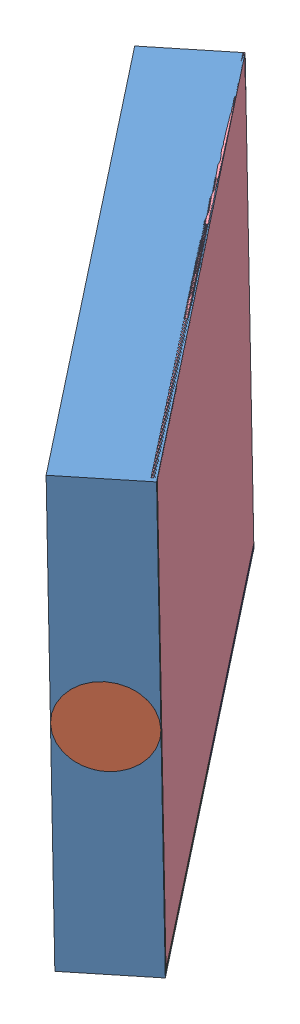
SolidWorks assembly 外层, configuration 默认. Lengths in mm.
Overall size (251.85 293.23 307.24).
20 component instances, 9 part files, 52 mates.
Components (placement in the parent):
- 外边-1: 外边 [默认] at (-96.6611 135.2786 -148.7016) x (0.616223 -0.016531 0.787398) z (-0.787571 -0.012292 0.616101) size (342 143.5 52)
- logo 7-2: logo 7 [默认] at (63.1533 32.4888 95.7419) x (-0.000506 -0.999788 -0.020594) z (-0.616223 0.016531 -0.787398) size (70 52 85)
- 外边-2: 外边 [默认] at (-137.7138 -60.625 -120.6864) x (0.616223 -0.016531 0.787398) z (0.787571 0.012292 -0.616101) size (342 143.5 52)
- 铝合金滑轨-1: 铝合金滑轨 [默认] at (-122.5192 -111.9948 -153.7845) x (0.787571 0.012292 -0.616101) z (0.616223 -0.016531 0.787398) size (9 6 30)
- 面板-1: 面板 [默认] at (-112.3031 122.2109 -89.4251) x (0.616223 -0.016531 0.787398) z (-0.787571 -0.012292 0.616101) size (339 284 3)
- 悬空支持-1: 悬空支持 [默认] at (-112.3091 -69.9933 -122.793) x (0.000506 0.999788 0.020594) z (-0.616223 0.016531 -0.787398) size (20 24.1 30)
- 滑槽上部-1: 滑槽上部 [默认] at (-106.0436 -86.5365 -128.0437) x (0.000506 0.999788 0.020594) z (-0.787571 -0.012292 0.616101) size (20 30 23)
- 悬空支持-2: 悬空支持 [默认] at (-6.7089 -73.0262 12.1368) x (0.000506 0.999788 0.020594) z (-0.616223 0.016531 -0.787398) size (20 24.1 30)
- 铝合金滑轨-6: 铝合金滑轨 [默认] at (-16.9191 -115.0277 -18.8547) x (0.787571 0.012292 -0.616101) z (0.616223 -0.016531 0.787398) size (9 6 30)
- 滑槽上部-2: 滑槽上部 [默认] at (-0.4435 -89.5693 6.8861) x (0.000506 0.999788 0.020594) z (-0.787571 -0.012292 0.616101) size (20 30 23)
- 悬空支持-3: 悬空支持 [默认] at (-131.7573 144.5854 -143.3729) x (-0.000506 -0.999788 -0.020594) z (0.616223 -0.016531 0.787398) size (20 24.1 30)
- 铝合金滑轨-7: 铝合金滑轨 [默认] at (-104.9508 186.846 -125.3644) x (0.787571 0.012292 -0.616101) z (-0.616223 0.016531 -0.787398) size (9 6 30)
- 滑槽上部-3: 滑槽上部 [默认] at (-125.475 161.3244 -147.9381) x (-0.000506 -0.999788 -0.020594) z (-0.787571 -0.012292 0.616101) size (20 30 23)
- 悬空支持-4: 悬空支持 [默认] at (-23.3299 141.6767 -4.8265) x (-0.000506 -0.999788 -0.020594) z (0.616223 -0.016531 0.787398) size (20 24.1 30)
- 铝合金滑轨-8: 铝合金滑轨 [默认] at (3.4766 183.9372 13.182) x (0.787571 0.012292 -0.616101) z (-0.616223 0.016531 -0.787398) size (9 6 30)
- 滑槽上部-4: 滑槽上部 [默认] at (-17.0475 158.4157 -9.3916) x (-0.000506 -0.999788 -0.020594) z (-0.787571 -0.012292 0.616101) size (20 30 23)
- 内边 logo-1: 内边 logo [默认] at (-4.6898 -53.8173 -34.9057) x (0.000506 0.999788 0.020594) z (-0.787571 -0.012292 0.616101) size (284 169.5 40)
- 内边  接口-1: 内边  接口 [默认] at (-53.3108 -91.0884 -32.878) x (0.616223 -0.016531 0.787398) z (0.787571 0.012292 -0.616101) size (171 284 52)
- 面板-2: 面板 [默认] at (-74.6356 124.3377 -120.7643) x (0.616223 -0.016531 0.787398) z (-0.787571 -0.012292 0.616101) size (339 284 3)
- 电源固定-1: 电源固定 [默认] at (1.3781 -67.6569 79.027) x (-0.616223 0.016531 -0.787398) z (-0.000506 -0.999788 -0.020594) size (84 42 40)
Mates (geometry in assembly coordinates):
- 重合6: coincident anti-aligned: plane of 铝合金滑轨-1 through (-126.6531 -104.8598 -112.2993) normal (-0.787571 -0.012292 0.616101); plane of 面板-1 through (-112.3031 122.2109 -89.4251) normal (0.787571 0.012292 -0.616101)
- 重合17: coincident anti-aligned: plane of 面板-1 through (-112.3031 122.2109 -89.4251) normal (0.787571 0.012292 -0.616101); plane of 悬空支持-1 through (-145.1359 -96.6655 -135.7626) normal (-0.787571 -0.012292 0.616101)
- 重合19: coincident anti-aligned: plane of 铝合金滑轨-1 through (-126.4139 -99.1573 -112.3667) normal (0.000506 0.999788 0.020594); plane of 悬空支持-1 through (-145.1369 -98.6651 -135.8038) normal (-0.000506 -0.999788 -0.020594)
- 重合20: coincident aligned: plane of 铝合金滑轨-1 through (-138.2879 -104.2569 -141.2813) normal (-0.616223 0.016531 -0.787398); plane of 悬空支持-1 through (-130.7958 -69.4974 -146.4149) normal (-0.616223 0.016531 -0.787398)
- 重合21: coincident anti-aligned: plane of 外边-1 through (41.824 174.1639 113.5037) normal (-0.616223 0.016531 -0.787398); plane of 面板-1 through (41.824 174.1639 113.5037) normal (0.616223 -0.016531 0.787398)
- 重合22: coincident aligned: plane of 外边-1 through (41.824 174.1639 113.5037) normal (-0.616223 0.016531 -0.787398); plane of 外边-2 through (82.6339 -109.1367 75.6178) normal (-0.616223 0.016531 -0.787398)
- 重合24: coincident aligned: plane of 外边-1 through (-137.6148 134.6394 -116.6643) normal (-0.787571 -0.012292 0.616101); plane of 面板-1 through (-114.6658 122.174 -87.5768) normal (-0.787571 -0.012292 0.616101)
- 重合25: coincident anti-aligned: plane of 外边-2 through (30.2549 -107.7315 8.689) normal (0.000506 0.999788 0.020594); plane of 面板-1 through (41.6802 -109.7758 107.655) normal (-0.000506 -0.999788 -0.020594)
- 重合26: coincident aligned: plane of 外边-2 through (-137.7138 -60.625 -120.6864) normal (-0.787571 -0.012292 0.616101); plane of 面板-1 through (-114.6658 122.174 -87.5768) normal (-0.787571 -0.012292 0.616101)
- 重合27: coincident anti-aligned: plane of 外边-1 through (-10.5549 175.5691 46.5749) normal (-0.000506 -0.999788 -0.020594); plane of 面板-1 through (-167.0757 179.768 -153.4242) normal (0.000506 0.999788 0.020594)
- 重合28: coincident anti-aligned: plane of 外边-1 through (41.824 174.1639 113.5037) normal (-0.616223 0.016531 -0.787398); plane of logo 7-2 through (62.229 32.5136 94.5608) normal (0.616223 -0.016531 0.787398)
- 同心1: concentric anti-aligned: cylinder of logo 7-2 through (62.229 32.5136 94.5608) axis (0.616223 -0.016531 0.787398) radius 26; cylinder of 外边-2 through (94.2726 31.654 135.5055) axis (-0.616223 0.016531 -0.787398) radius 26
- 重合29: coincident anti-aligned: plane of 悬空支持-1 through (-126.1586 -102.6679 -150.7404) normal (0.787571 0.012292 -0.616101); plane of 滑槽上部-1 through (-126.1586 -102.6679 -150.7404) normal (-0.787571 -0.012292 0.616101)
- 重合30: coincident aligned: plane of 悬空支持-1 through (-126.1485 -82.6722 -150.3285) normal (0.000506 0.999788 0.020594); plane of 滑槽上部-1 through (-126.1485 -82.6722 -150.3285) normal (0.000506 0.999788 0.020594)
- 重合31: coincident aligned: plane of 悬空支持-1 through (-112.3091 -69.9933 -122.793) normal (0.616223 -0.016531 0.787398); plane of 滑槽上部-1 through (-106.0436 -86.5365 -128.0437) normal (0.616223 -0.016531 0.787398)
- 重合32: coincident anti-aligned: plane of logo 7-2 through (72.3129 -2.2821 84.0335) normal (0.787571 0.012292 -0.616101); plane of 内边 logo-1 through (96.3455 -3.1267 114.7379) normal (-0.787571 -0.012292 0.616101)
- 重合33: coincident anti-aligned: plane of 外边-2 through (30.2549 -107.7315 8.689) normal (0.000506 0.999788 0.020594); plane of 内边 logo-1 through (-53.3188 -106.8263 -33.2021) normal (-0.000506 -0.999788 -0.020594)
- 重合34: coincident anti-aligned: plane of 外边-2 through (82.6339 -109.1367 75.6178) normal (-0.616223 0.016531 -0.787398); plane of 内边 logo-1 through (51.1311 -109.6283 100.2618) normal (0.616223 -0.016531 0.787398)
- 重合35: coincident anti-aligned: plane of 铝合金滑轨-1 through (-119.5649 -104.7492 -117.8442) normal (0.787571 0.012292 -0.616101); plane of 内边  接口-1 through (-53.3108 -91.0884 -32.878) normal (-0.787571 -0.012292 0.616101)
- 重合36: coincident anti-aligned: plane of 外边-2 through (30.2549 -107.7315 8.689) normal (0.000506 0.999788 0.020594); plane of 内边  接口-1 through (-21.8159 -106.3346 -57.8462) normal (-0.000506 -0.999788 -0.020594)
- 重合37: coincident aligned: plane of 外边-2 through (-127.1909 -105.0074 -192.5221) normal (-0.616223 0.016531 -0.787398); plane of 内边  接口-1 through (-158.685 -88.2615 -167.523) normal (-0.616223 0.016531 -0.787398)
- 重合53: coincident anti-aligned: plane of 悬空支持-2 through (-39.5368 -101.6979 -0.874) normal (-0.000506 -0.999788 -0.020594); plane of 铝合金滑轨-6 through (-20.8138 -102.1902 22.5631) normal (0.000506 0.999788 0.020594)
- 重合54: coincident aligned: plane of 悬空支持-2 through (-6.7089 -73.0262 12.1368) normal (0.616223 -0.016531 0.787398); plane of 铝合金滑轨-6 through (-14.2011 -107.7857 17.2704) normal (0.616223 -0.016531 0.787398)
- 重合55: coincident anti-aligned: plane of 悬空支持-2 through (-20.5585 -105.7008 -15.8106) normal (0.787571 0.012292 -0.616101); plane of 滑槽上部-2 through (-20.5585 -105.7008 -15.8106) normal (-0.787571 -0.012292 0.616101)
- 重合56: coincident aligned: plane of 悬空支持-2 through (-20.5483 -85.705 -15.3987) normal (0.000506 0.999788 0.020594); plane of 滑槽上部-2 through (-20.5483 -85.705 -15.3987) normal (0.000506 0.999788 0.020594)
- 重合57: coincident aligned: plane of 悬空支持-2 through (-25.1956 -72.5303 -11.4851) normal (-0.616223 0.016531 -0.787398); plane of 滑槽上部-2 through (-18.9302 -89.0734 -16.7358) normal (-0.616223 0.016531 -0.787398)
- 重合58: coincident anti-aligned: plane of 悬空支持-3 through (-127.5824 172.81 -107.9475) normal (0.000506 0.999788 0.020594); plane of 铝合金滑轨-7 through (-145.8328 173.3096 -131.7543) normal (-0.000506 -0.999788 -0.020594)
- 重合59: coincident aligned: plane of 悬空支持-3 through (-131.7573 144.5854 -143.3729) normal (-0.616223 0.016531 -0.787398); plane of 铝合金滑轨-7 through (-139.2143 179.1117 -136.8121) normal (-0.616223 0.016531 -0.787398)
- 重合60: coincident anti-aligned: plane of 悬空支持-3 through (-108.5998 177.4053 -122.707) normal (0.787571 0.012292 -0.616101); plane of 滑槽上部-3 through (-108.5998 177.4053 -122.707) normal (-0.787571 -0.012292 0.616101)
- 重合61: coincident aligned: plane of 悬空支持-3 through (-108.6099 157.4096 -123.1189) normal (-0.000506 -0.999788 -0.020594); plane of 滑槽上部-3 through (-108.6099 157.4096 -123.1189) normal (-0.000506 -0.999788 -0.020594)
- 重合62: coincident aligned: plane of 悬空支持-3 through (-113.2706 144.0895 -119.751) normal (0.616223 -0.016531 0.787398); plane of 滑槽上部-3 through (-106.9883 160.8285 -124.3161) normal (0.616223 -0.016531 0.787398)
- 重合63: coincident anti-aligned: plane of 悬空支持-4 through (-19.155 169.9012 30.599) normal (0.000506 0.999788 0.020594); plane of 铝合金滑轨-8 through (-37.4054 170.4009 6.7922) normal (-0.000506 -0.999788 -0.020594)
- 重合64: coincident aligned: plane of 悬空支持-4 through (-4.8432 141.1807 18.7955) normal (0.616223 -0.016531 0.787398); plane of 铝合金滑轨-8 through (-12.3002 175.707 25.3563) normal (0.616223 -0.016531 0.787398)
- 重合65: coincident anti-aligned: plane of 悬空支持-4 through (-0.1723 174.4965 15.8395) normal (0.787571 0.012292 -0.616101); plane of 滑槽上部-4 through (-0.1723 174.4965 15.8395) normal (-0.787571 -0.012292 0.616101)
- 重合66: coincident aligned: plane of 悬空支持-4 through (-0.1824 154.5008 15.4276) normal (-0.000506 -0.999788 -0.020594); plane of 滑槽上部-4 through (-0.1824 154.5008 15.4276) normal (-0.000506 -0.999788 -0.020594)
- 重合67: coincident aligned: plane of 悬空支持-4 through (-23.3299 141.6767 -4.8265) normal (-0.616223 0.016531 -0.787398); plane of 滑槽上部-4 through (-17.0475 158.4157 -9.3916) normal (-0.616223 0.016531 -0.787398)
- 重合73: coincident anti-aligned: plane of 滑槽上部-2 through (-2.4443 -105.4181 -29.9809) normal (-0.000506 -0.999788 -0.020594); plane of 内边 logo-1 through (50.2075 -108.1038 99.1116) normal (0.000506 0.999788 0.020594)
- 重合74: coincident anti-aligned: plane of 面板-1 through (-112.3031 122.2109 -89.4251) normal (0.787571 0.012292 -0.616101); plane of 悬空支持-2 through (-39.5358 -99.6984 -0.8329) normal (-0.787571 -0.012292 0.616101)
- 重合75: coincident anti-aligned: plane of 外边-2 through (30.2549 -107.7315 8.689) normal (0.000506 0.999788 0.020594); plane of 铝合金滑轨-1 through (-126.417 -105.156 -112.4903) normal (-0.000506 -0.999788 -0.020594)
- 重合76: coincident anti-aligned: plane of 外边-1 through (-10.5549 175.5691 46.5749) normal (-0.000506 -0.999788 -0.020594); plane of 铝合金滑轨-7 through (-145.8298 179.3083 -131.6307) normal (0.000506 0.999788 0.020594)
- 重合77: coincident anti-aligned: plane of 面板-1 through (-112.3031 122.2109 -89.4251) normal (0.787571 0.012292 -0.616101); plane of 铝合金滑轨-7 through (-146.0662 179.0047 -131.452) normal (-0.787571 -0.012292 0.616101)
- 重合78: coincident anti-aligned: plane of 面板-1 through (-112.3031 122.2109 -89.4251) normal (0.787571 0.012292 -0.616101); plane of 悬空支持-3 through (-127.5834 170.8104 -107.9887) normal (-0.787571 -0.012292 0.616101)
- 重合79: coincident anti-aligned: plane of 面板-1 through (-112.3031 122.2109 -89.4251) normal (0.787571 0.012292 -0.616101); plane of 铝合金滑轨-8 through (-37.6388 176.096 7.0944) normal (-0.787571 -0.012292 0.616101)
- 重合80: coincident anti-aligned: plane of 外边-1 through (-10.5549 175.5691 46.5749) normal (-0.000506 -0.999788 -0.020594); plane of 铝合金滑轨-8 through (-37.4023 176.3996 6.9158) normal (0.000506 0.999788 0.020594)
- 重合81: coincident anti-aligned: plane of 面板-1 through (-112.3031 122.2109 -89.4251) normal (0.787571 0.012292 -0.616101); plane of 悬空支持-4 through (-19.156 167.9017 30.5578) normal (-0.787571 -0.012292 0.616101)
- 重合82: coincident anti-aligned: plane of 面板-1 through (-112.3031 122.2109 -89.4251) normal (0.787571 0.012292 -0.616101); plane of 铝合金滑轨-6 through (-21.053 -107.8927 22.6305) normal (-0.787571 -0.012292 0.616101)
- 重合83: coincident anti-aligned: plane of 内边 logo-1 through (50.2075 -108.1038 99.1116) normal (0.000506 0.999788 0.020594); plane of 面板-2 through (79.3476 -107.649 76.3159) normal (-0.000506 -0.999788 -0.020594)
- 重合84: coincident anti-aligned: plane of 内边 logo-1 through (50.3498 172.8365 104.8985) normal (-0.616223 0.016531 -0.787398); plane of 面板-2 through (79.4915 176.2907 82.1646) normal (0.616223 -0.016531 0.787398)
- 重合85: coincident aligned: plane of 内边 logo-1 through (-4.6898 -53.8173 -34.9057) normal (0.787571 0.012292 -0.616101); plane of 面板-2 through (-74.6356 124.3377 -120.7643) normal (0.787571 0.012292 -0.616101)
- 重合88: coincident aligned: plane of logo 7-2 through (10.7743 33.894 28.813) normal (-0.616223 0.016531 -0.787398); plane of 电源固定-1 through (25.667 -106.3427 14.2137) normal (-0.616223 0.016531 -0.787398)
- 重合89: coincident anti-aligned: plane of 面板-1 through (-112.3031 122.2109 -89.4251) normal (0.787571 0.012292 -0.616101); plane of 电源固定-1 through (-7.411 -106.8589 40.0899) normal (-0.787571 -0.012292 0.616101)
- 重合90: coincident anti-aligned: plane of 内边 logo-1 through (50.2075 -108.1038 99.1116) normal (0.000506 0.999788 0.020594); plane of 电源固定-1 through (1.3579 -107.6484 78.2032) normal (-0.000506 -0.999788 -0.020594)
